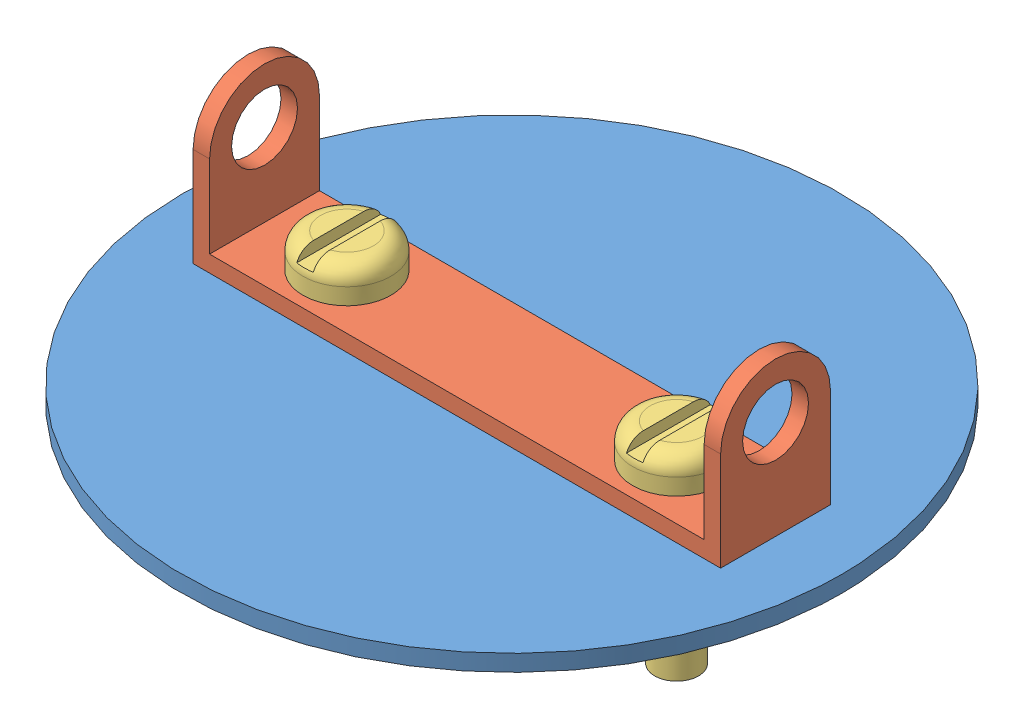
SolidWorks assembly Assem1, configuration Default. Lengths in mm.
Overall size (60 28.5 60).
8 component instances, 5 part files, 18 mates.
Components (placement in the parent):
- Plate^Assem1-1: Plate^Assem1 [Default] x (1 0 0) z (0 -1 0) size (60 60 1.5) (virtual)
- Bearing Housing^Assem1-1: Bearing Housing^Assem1 [Default] at (0 7 -5) size (48 14 10) (virtual)
- pan slot head_am-1: pan slot head_am [B18.6.7M - M4 x 0.7 x 16 Slotted PHMS --16N] at (15 4.6 0) x (0 -1 0) z (0 0 1) size (19.1 8 8)
- pan slot head_am-2: pan slot head_am [B18.6.7M - M4 x 0.7 x 16 Slotted PHMS --16N] at (-15 4.6 0) x (0 -1 0) z (0 0 1) size (19.1 8 8)
- flat washer regular_am-1: flat washer regular_am [B18.22M - Plain washer, 4 mm, regular] at (15 -2.9 0) x (0 -1 0) z (0.709873 0 0.70433) size (1.4 12 12)
- flat washer regular_am-2: flat washer regular_am [B18.22M - Plain washer, 4 mm, regular] at (-15 -2.9 0) x (0 -1 0) z (0.54169 0 0.840578) size (1.4 12 12)
- hex nut style 1_am-1: hex nut style 1_am [B18.2.4.1M - Hex nut, Style 1,  M4 x 0.7 --D-N] at (-15 -2.9 0) x (0.998717 0 -0.050643) z (0 1 0) size (7 8.08 3.2)
- hex nut style 1_am-2: hex nut style 1_am [B18.2.4.1M - Hex nut, Style 1,  M4 x 0.7 --D-N] at (15 -2.9 0) x (0.981403 0 0.191961) z (0 1 0) size (7 8.08 3.2)
Mates (geometry in assembly coordinates):
- Coincident4: coincident: point of Plate^Assem1-1; point of assembly
- Parallel1: parallel: plane of Plate^Assem1-1 through (0 -1.5 0) normal (0 -1 0); plane of assembly through (0 0 0) normal (0 1 0)
- Coincident5: coincident: plane of Plate^Assem1-1 through (0 0 0) normal (0 0 1); plane of assembly through (0 0 0) normal (0 0 1)
- Concentric1: concentric: cylinder of Plate^Assem1-1 through (15 -1.5 0) axis (0 1 0) radius 2; cylinder of Bearing Housing^Assem1-1 through (15 -8.5 0) axis (0 1 0) radius 3
- Concentric2: concentric: cylinder of Plate^Assem1-1 through (-15 -1.5 0) axis (0 1 0) radius 2; cylinder of Bearing Housing^Assem1-1 through (-15 -8.5 0) axis (0 1 0) radius 2
- Coincident9: coincident: plane of Plate^Assem1-1 through (0 0 0) normal (0 1 0); plane of Bearing Housing^Assem1-1 through (-24 0 5) normal (0 -1 0)
- Concentric4: concentric: cylinder of Bearing Housing^Assem1-1 through (15 -8.5 0) axis (0 1 0) radius 3; cylinder of pan slot head_am-1 through (15 30 0) axis (0 1 0) radius 4
- Coincident11: coincident: plane of Bearing Housing^Assem1-1 through (-22.5 1.5 5) normal (0 1 0); plane of pan slot head_am-1 through (17 1.5 0) normal (0 -1 0)
- Concentric5: concentric: cylinder of Bearing Housing^Assem1-1 through (-15 -8.5 0) axis (0 1 0) radius 2; cylinder of pan slot head_am-2 through (-15 30 0) axis (0 1 0) radius 4
- Coincident12: coincident: plane of Bearing Housing^Assem1-1 through (-22.5 1.5 5) normal (0 1 0); plane of pan slot head_am-2 through (-13 1.5 0) normal (0 -1 0)
- Concentric6: concentric: cylinder of pan slot head_am-1 through (15 30 0) axis (0 1 0) radius 2; cylinder of flat washer regular_am-1 through (15 32.025 0) axis (0 1 0) radius 2.44
- Concentric7: concentric: cylinder of pan slot head_am-2 through (-15 30 0) axis (0 1 0) radius 2; cylinder of flat washer regular_am-2 through (-15 32.025 0) axis (0 1 0) radius 2.44
- Coincident14: coincident: plane of Plate^Assem1-1 through (0 -1.5 0) normal (0 -1 0); plane of flat washer regular_am-2 through (-9.9565 -1.5 -3.2501) normal (0 1 0)
- Coincident15: coincident: plane of Plate^Assem1-1 through (0 -1.5 0) normal (0 -1 0); plane of flat washer regular_am-1 through (19.226 -1.5 -4.2592) normal (0 1 0)
- Concentric8: concentric: cylinder of pan slot head_am-2 through (-15 30 0) axis (0 1 0) radius 2; cylinder of hex nut style 1_am-1 through (-15 -34.4738 0) axis (0 1 0) radius 2
- Concentric9: concentric: cylinder of pan slot head_am-1 through (15 30 0) axis (0 1 0) radius 2; cylinder of hex nut style 1_am-2 through (15 -35.0332 0) axis (0 1 0) radius 2
- Coincident16: coincident: plane of flat washer regular_am-2 through (-12.949 -2.9 -1.3217) normal (0 -1 0); plane of hex nut style 1_am-1 through (-15.2047 -2.9 -4.0363) normal (0 1 0)
- Coincident17: coincident: plane of flat washer regular_am-1 through (16.7186 -2.9 -1.7321) normal (0 -1 0); plane of hex nut style 1_am-2 through (15.7758 -2.9 -3.9663) normal (0 1 0)
